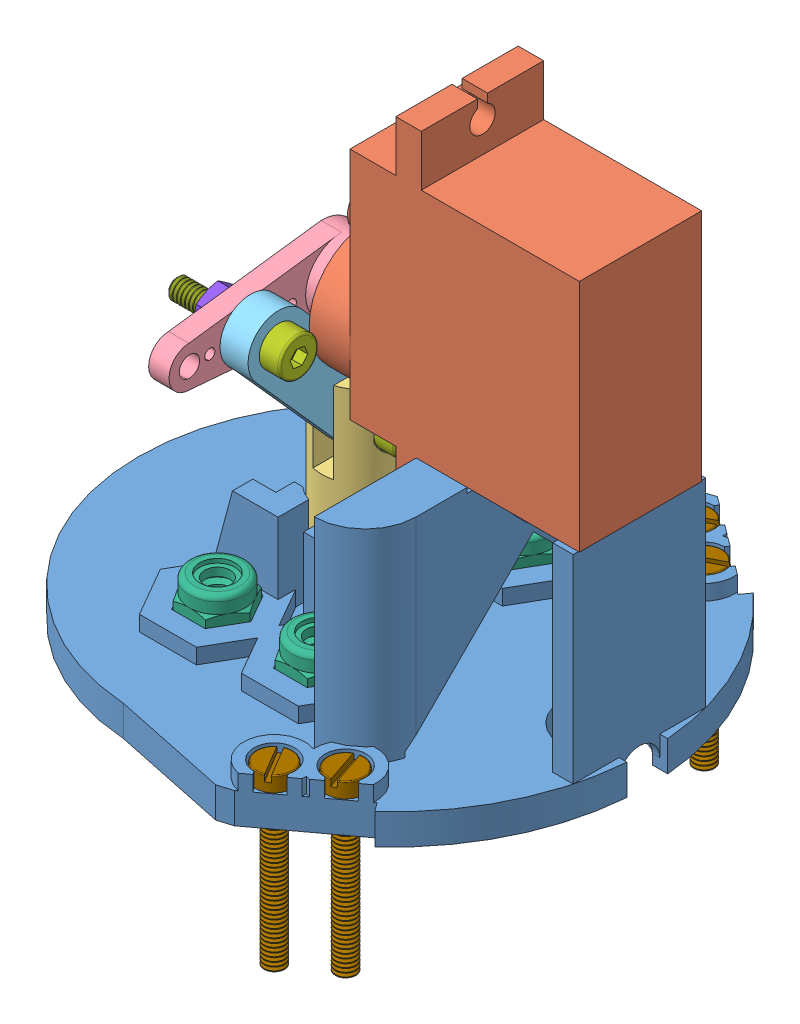
SolidWorks assembly Rückseite, configuration Standard. Lengths in mm.
Overall size (49.92 63.5 48.18).
20 component instances, 10 part files, 43 mates.
Components (placement in the parent):
- Backside-1: Backside [Standard] at (-0.7502 -6.4244 50) size (49.92 23 48.18)
- servo-1: servo [Standard] at (26.7498 39.0756 44) x (0 -1 0) z (0 0 -1) size (33 29.25 12)
- Druecker-1: Druecker [Standard] at (-0.7502 15.8004 50) x (0 0 -1) z (-1 0 0) size (7.5 28 7.5)
- Servo-Arm-1: Servo-Arm [Standard] at (-4.5002 22.0756 50) x (0 -0.023408 0.999726) z (0 0.999726 0.023408) size (20.6 4.3 7.2)
- Hebel2-1: Hebel2 [Standard] at (-1.7502 11.8004 50) x (0 0.745519 0.666484) z (0 0.666484 -0.745519) size (19.5 2.75 6)
- User Library-Mutter DIN-985_-1: User Library-Mutter DIN-985_ [Mutter DIN-985 M3-A2] at (-4.7502 -3.4244 60) x (0 1 0) z (0 0 1) size (4 6.35 5.5)
- User Library-Mutter DIN-985_-2: User Library-Mutter DIN-985_ [Mutter DIN-985 M3-A2] at (5.2498 -3.4244 60) x (0 1 0) z (-0.866025 0 0.5) size (4 6.35 5.5)
- User Library-Mutter DIN-985_-3: User Library-Mutter DIN-985_ [Mutter DIN-985 M3-A2] at (5.2498 -3.4244 40) x (0 1 0) z (-0.866025 0 -0.5) size (4 6.35 5.5)
- User Library-Mutter DIN-985_-4: User Library-Mutter DIN-985_ [Mutter DIN-985 M3-A2] at (-4.7502 -3.4244 40) x (0 1 0) z (-0.866025 0 0.5) size (4 6.35 5.5)
- socket head cap screw 4762_din-2: socket head cap screw 4762_din [ISO 4762 M2 x 10 --- 10S] at (4.4998 11.8004 50) x (-1 0 0) z (0 0.998185 -0.060223) size (12 3.8 3.8)
- socket head cap screw 4762_din-3: socket head cap screw 4762_din [ISO 4762 M2 x 10 --- 10S] at (2.2498 21.865 58.9975) x (-1 0 0) z (0 -0.636606 -0.77119) size (12 3.8 3.8)
- nut__style_1__m2x0_4__ansi_b18_2_4_1m-1: nut__style_1__m2x0_4__ansi_b18_2_4_1m [Default] at (-4.0002 11.8004 50) x (0 -0.5 -0.866025) z (-1 0 0) size (4.62 4 1.6)
- nut__style_1__m2x0_4__ansi_b18_2_4_1m-2: nut__style_1__m2x0_4__ansi_b18_2_4_1m [Default] at (-6.1002 21.865 58.9975) x (0 0.584705 0.811246) z (1 0 0) size (4.62 4 1.6)
- slotted cheese head screw_din-1: slotted cheese head screw_din [ISO 1207 - M2 x 16 --- 16S] at (11.3929 -2.0244 70.5635) x (0 -1 0) z (0.511563 0 0.859246) size (17.41 3.8 3.8)
- slotted cheese head screw_din-2: slotted cheese head screw_din [ISO 1207 - M2 x 16 --- 16S] at (11.3929 -2.0244 29.4365) x (0 -1 0) z (-0.876101 0 0.482128) size (17.41 3.8 3.8)
- slotted cheese head screw_din-3: slotted cheese head screw_din [ISO 1207 - M2 x 16 --- 16S] at (15.4084 -2.0244 32.4156) x (0 -1 0) z (-0.890448 0 0.455085) size (17.41 3.8 3.8)
- slotted cheese head screw_din-4: slotted cheese head screw_din [ISO 1207 - M2 x 16 --- 16S] at (15.4084 -2.0244 67.5844) x (0 -1 0) z (0.315666 0 0.94887) size (17.41 3.8 3.8)
- cross fh tapping 7976_din-2: cross fh tapping 7976_din [Tapping screw DIN 7982-ST2.9x6.5-C-Z-S] at (-5.2502 22.0756 50) x (1 0 0) z (0 0.296413 0.95506) size (6.51 5.5 5.5)
- slotted cheese head screw_din-7: slotted cheese head screw_din [ISO 1207 - M2 x 16 --- 16S] at (7.3498 13.0756 50) x (1 0 0) z (0 0.315666 0.94887) size (17.41 3.8 3.8)
- nut__style_1__m2x0_4__ansi_b18_2_4_1m-5: nut__style_1__m2x0_4__ansi_b18_2_4_1m [Default] at (16.2498 13.0756 50) x (0 0.584705 0.811246) z (1 0 0) size (4.62 4 1.6)
Mates (geometry in assembly coordinates):
- Konzentrisch1: concentric anti-aligned: cylinder of Druecker-1 through (-0.7502 -12.1996 50) axis (0 1 0) radius 3.75; cylinder of Backside-1 through (-0.7502 -3.4244 50) axis (0 -1 0) radius 4
- Konzentrisch3: concentric anti-aligned: cylinder of servo-1 through (0.2498 22.0756 50) axis (1 0 0) radius 6; cylinder of Servo-Arm-1 through (-0.2002 22.0756 50) axis (-1 0 0) radius 2.25
- Deckungsgleich9: coincident anti-aligned: plane of Hebel2-1 through (-2.5002 21.865 58.9975) normal (-1 0 0); plane of Servo-Arm-1 through (-2.5002 22.0756 50) normal (1 0 0)
- Deckungsgleich12: coincident anti-aligned: plane of servo-1 through (-2.5002 22.0756 50) normal (-1 0 0); plane of Servo-Arm-1 through (-2.5002 22.0756 50) normal (1 0 0)
- Konzentrisch5: concentric aligned: cylinder of Hebel2-1 through (0.2498 21.865 58.9975) axis (-1 0 0) radius 1.15; cylinder of Servo-Arm-1 through (-2.5002 21.865 58.9975) axis (-1 0 0) radius 0.5
- Deckungsgleich28: coincident anti-aligned: plane of Backside-1 through (-0.7502 -3.4244 50) normal (0 1 0); plane of User Library-Mutter DIN-985_-1 through (-7.4789 -3.4244 60) normal (0 -1 0)
- Deckungsgleich29: coincident anti-aligned: plane of Backside-1 through (-0.7502 -3.4244 50) normal (0 1 0); plane of User Library-Mutter DIN-985_-2 through (3.8855 -3.4244 57.6369) normal (0 -1 0)
- Deckungsgleich31: coincident anti-aligned: plane of Backside-1 through (-0.7502 -3.4244 50) normal (0 1 0); plane of User Library-Mutter DIN-985_-3 through (6.6142 -3.4244 37.6369) normal (0 -1 0)
- Deckungsgleich30: coincident anti-aligned: plane of Backside-1 through (-0.7502 -3.4244 50) normal (0 1 0); plane of User Library-Mutter DIN-985_-4 through (-6.1145 -3.4244 37.6369) normal (0 -1 0)
- Konzentrisch19: concentric anti-aligned: cylinder of Druecker-1 through (3.2498 11.8004 50) axis (-1 0 0) radius 1.1; cylinder of socket head cap screw 4762_din-2 through (36.2498 11.8004 50) axis (1 0 0) radius 1
- Deckungsgleich38: coincident anti-aligned: plane of Hebel2-1 through (0.2498 11.8004 50) normal (1 0 0); plane of socket head cap screw 4762_din-3 through (0.2498 23.3302 57.788) normal (-1 0 0)
- Konzentrisch38: concentric anti-aligned: cylinder of Hebel2-1 through (0.2498 21.865 58.9975) axis (-1 0 0) radius 1.15; cylinder of socket head cap screw 4762_din-3 through (33.9998 21.865 58.9975) axis (1 0 0) radius 1
- Deckungsgleich41: coincident anti-aligned: plane of Druecker-1 through (-4.0002 15.8004 50) normal (-1 0 0); plane of nut__style_1__m2x0_4__ansi_b18_2_4_1m-1 through (-4.0002 10.6454 47.9995) normal (1 0 0)
- Konzentrisch49: concentric aligned: circle of socket head cap screw 4762_din-2; circle of nut__style_1__m2x0_4__ansi_b18_2_4_1m-1
- Konzentrisch50: concentric anti-aligned: circle of socket head cap screw 4762_din-3; circle of nut__style_1__m2x0_4__ansi_b18_2_4_1m-2
- Konzentrisch51: concentric aligned: circle of Backside-1; circle of User Library-Mutter DIN-985_-1
- Konzentrisch52: concentric aligned: circle of Backside-1; circle of User Library-Mutter DIN-985_-2
- Konzentrisch53: concentric aligned: circle of Backside-1; circle of User Library-Mutter DIN-985_-4
- Konzentrisch54: concentric aligned: circle of Backside-1; circle of User Library-Mutter DIN-985_-3
- Deckungsgleich40: coincident anti-aligned: plane of Druecker-1 through (2.4998 11.8004 50) normal (1 0 0); plane of socket head cap screw 4762_din-2 through (2.4998 11.9149 51.8966) normal (-1 0 0)
- Konzentrisch59: concentric anti-aligned: cylinder of Backside-1 through (15.4084 -3.4244 32.4156) axis (0 -1 0) radius 1.1; cylinder of slotted cheese head screw_din-3 through (15.4084 23.3756 32.4156) axis (0 1 0) radius 1
- Konzentrisch60: concentric anti-aligned: cylinder of Backside-1 through (11.3929 -3.4244 29.4365) axis (0 -1 0) radius 1.1; cylinder of slotted cheese head screw_din-2 through (11.3929 23.3756 29.4365) axis (0 1 0) radius 1
- Konzentrisch61: concentric anti-aligned: cylinder of Backside-1 through (15.4084 -3.4244 67.5844) axis (0 -1 0) radius 1.1; cylinder of slotted cheese head screw_din-4 through (15.4084 23.3756 67.5844) axis (0 1 0) radius 1
- Konzentrisch62: concentric anti-aligned: cylinder of Backside-1 through (11.3929 -3.4244 70.5635) axis (0 -1 0) radius 1.1; cylinder of slotted cheese head screw_din-1 through (11.3929 23.3756 70.5635) axis (0 1 0) radius 1
- Deckungsgleich42: coincident anti-aligned: plane of Backside-1 through (-0.7502 -3.4244 50) normal (0 1 0); plane of slotted cheese head screw_din-3 through (15.8635 -3.4244 33.306) normal (0 -1 0)
- Deckungsgleich43: coincident anti-aligned: plane of Backside-1 through (-0.7502 -3.4244 50) normal (0 1 0); plane of slotted cheese head screw_din-2 through (11.875 -3.4244 30.3126) normal (0 -1 0)
- Deckungsgleich44: coincident anti-aligned: plane of Backside-1 through (-0.7502 -3.4244 50) normal (0 1 0); plane of slotted cheese head screw_din-1 through (12.2521 -3.4244 70.052) normal (0 -1 0)
- Deckungsgleich45: coincident anti-aligned: plane of Backside-1 through (-0.7502 -3.4244 50) normal (0 1 0); plane of slotted cheese head screw_din-4 through (16.3573 -3.4244 67.2687) normal (0 -1 0)
- Deckungsgleich50: coincident: circle of Servo-Arm-1; cone of cross fh tapping 7976_din-2 through (-3.5502 22.0756 50) axis (1 0 0)
- Parallel2: parallel anti-aligned: plane of Backside-1 through (10.5481 -1.9244 43.4769) normal (-0.866025 0 0.5); plane of User Library-Mutter DIN-985_-3 through (8.4252 0.5766 40) normal (0.866025 0 -0.5)
- Parallel3: parallel anti-aligned: plane of Backside-1 through (3.0481 -1.9244 47.8071) normal (-0.866025 0 0.5); plane of User Library-Mutter DIN-985_-4 through (-1.5748 0.5766 40) normal (0.866025 0 -0.5)
- Parallel4: parallel anti-aligned: plane of Backside-1 through (3.0481 -1.9244 52.1929) normal (-0.866025 0 -0.5); plane of User Library-Mutter DIN-985_-1 through (-3.1625 0.5766 62.75) normal (0.866025 0 0.5)
- Parallel5: parallel anti-aligned: plane of Backside-1 through (10.5481 -1.9244 56.5231) normal (-0.866025 0 -0.5); plane of User Library-Mutter DIN-985_-2 through (6.8375 0.5766 62.75) normal (0.866025 0 0.5)
- Parallel6: parallel anti-aligned: plane of Druecker-1 through (-4.0002 12.984 52.05) normal (0 -0.866025 -0.5); plane of nut__style_1__m2x0_4__ansi_b18_2_4_1m-1 through (-5.6002 12.9554 52.0005) normal (0 0.866025 0.5)
- Deckungsgleich51: coincident anti-aligned: plane of servo-1 through (11.2498 11.0756 44) normal (1 0 0); plane of Backside-1 through (11.2498 -6.4244 50) normal (-1 0 0)
- Deckungsgleich58: coincident anti-aligned: plane of Backside-1 through (16.2498 16.0756 56.5) normal (0 1 0); plane of servo-1 through (4.2498 16.0756 44) normal (0 -1 0)
- Konzentrisch70: concentric aligned: cylinder of Backside-1 through (16.2498 13.0756 50) axis (-1 0 0) radius 1.1; cylinder of servo-1 through (16.7498 13.0756 50) axis (-1 0 0) radius 1.25
- Konzentrisch71: concentric aligned: cylinder of Druecker-1 through (3.2498 11.8004 50) axis (-1 0 0) radius 1.1; cylinder of Hebel2-1 through (0.2498 11.8004 50) axis (-1 0 0) radius 1.15
- Deckungsgleich59: coincident anti-aligned: plane of Servo-Arm-1 through (-4.5002 22.0756 50) normal (-1 0 0); plane of nut__style_1__m2x0_4__ansi_b18_2_4_1m-2 through (-4.5002 23.2156 60.8715) normal (1 0 0)
- Konzentrisch72: concentric aligned: cylinder of Backside-1 through (16.2498 13.0756 50) axis (-1 0 0) radius 1.1; cylinder of slotted cheese head screw_din-7 through (-18.0502 13.0756 50) axis (-1 0 0) radius 1
- Deckungsgleich60: coincident anti-aligned: plane of servo-1 through (8.7498 11.0756 44) normal (-1 0 0); plane of slotted cheese head screw_din-7 through (8.7498 14.0245 49.6843) normal (1 0 0)
- Deckungsgleich61: coincident anti-aligned: plane of Backside-1 through (16.2498 -6.4244 50) normal (1 0 0); plane of nut__style_1__m2x0_4__ansi_b18_2_4_1m-5 through (16.2498 14.4263 51.874) normal (-1 0 0)
- Konzentrisch73: concentric aligned: cylinder of Backside-1 through (16.2498 13.0756 50) axis (-1 0 0) radius 1.1; cylinder of nut__style_1__m2x0_4__ansi_b18_2_4_1m-5 through (16.2498 13.0756 50) axis (-1 0 0) radius 0.7835
